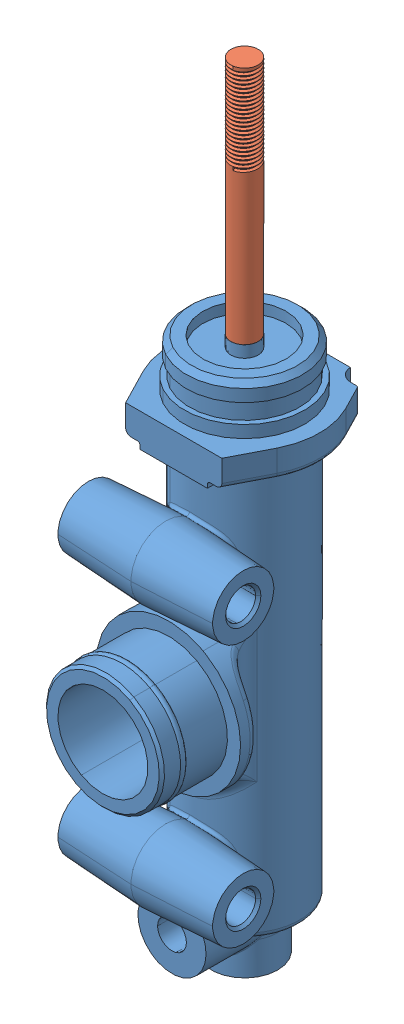
SolidWorks assembly Wilwood Master Cylinder, configuration Default. Lengths in mm.
Overall size (44.96 224.9 62.16).
2 component instances, 2 part files, 2 mates.
Components (placement in the parent):
- Wilwood MC 260-XXXX.stp-1: Wilwood MC 260-XXXX.stp [Default] at (-1090.1803 344.1862 374.5584) size (44.96 155.3 62.16)
- Part2^Wilwood Master Cylinder-1: Part2^Wilwood Master Cylinder [Default] at (-1090.1803 358.2644 374.5584) x (-0.149121 0 -0.988819) z (0 1 0) size (7.94 7.94 69.6) (virtual)
Mates (geometry in assembly coordinates):
- Concentric1: concentric aligned: cylinder of Wilwood MC 260-XXXX.stp-1 through (-1090.1803 327.4222 374.5584) axis (0 -1 0) radius 3.9688; cylinder of Part2^Assem1-1 through (-1090.1803 427.8604 374.5584) axis (0 -1 0) radius 3.9688
- LimitDistance3: limit distance = 0 mm anti-aligned: plane of Part2^Assem1-1 through (-1090.1803 358.2644 374.5584) normal (0 -1 0); plane of Wilwood MC 260-XXXX.stp-1 through (-1112.6593 358.2644 395.1284) normal (0 1 0)
